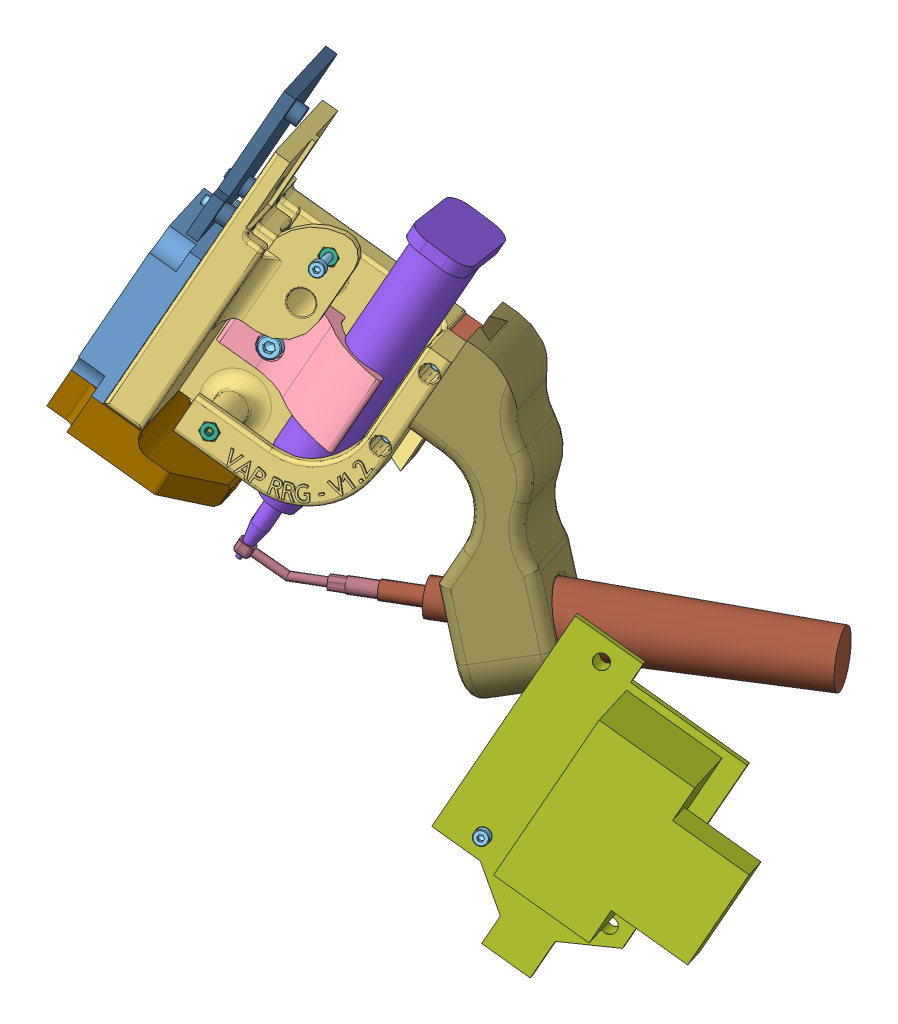
SolidWorks assembly nozzle4_assembly, configuration Default. Lengths in mm.
Overall size (190.12 193.79 108.62).
25 component instances, 13 part files, 57 mates.
Components (placement in the parent):
- fan-1: fan [Default] at (124.8712 147.7754 268.9855) x (0.468422 0.309997 0.827335) z (-0.270776 -0.840989 0.468422) size (40 10 40)
- nozzle4_QuickChange-1: nozzle4_QuickChange [Default] at (125.8081 148.3954 270.6402) x (0.840989 -0.443441 -0.309997) z (0.468422 0.309997 0.827335) size (8.5 30 13)
- nozzle4_quickmount-1: nozzle4_quickmount [Default] at (124.8712 147.7754 268.9855) x (0.840989 -0.443441 -0.309997) z (0.468422 0.309997 0.827335) size (60.2 70.01 40.1)
- syringe_clamp-1: syringe_clamp [Default] at (160.8249 151.5202 262.3349) x (0.840989 -0.443441 -0.309997) z (0.468422 0.309997 0.827335) size (35 20 18.86)
- socket head cap screw_am-1: socket head cap screw_am [B18.3.1M - 3 x 0.5 x 10 Hex SHCS -- 10NHX] at (157.0088 167.862 259.581) x (-0.468422 -0.309997 -0.827335) z (0.782372 0.289501 -0.551438) size (13 5.5 5.5)
- socket head cap screw_am-2: socket head cap screw_am [B18.3.1M - 3 x 0.5 x 10 Hex SHCS -- 10NHX] at (154.8426 161.1341 263.3283) x (-0.468422 -0.309997 -0.827335) z (0.782372 0.289501 -0.551438) size (13 5.5 5.5)
- hex nut style 1_am-1: hex nut style 1_am [B18.2.4.1M - Hex nut, Style 1,  M3 x 0.5 --D-N] at (150.1584 158.0341 255.055) x (0.801769 -0.542524 -0.250666) z (0.468422 0.309997 0.827335) size (5.5 6.35 2.4)
- hex nut style 1_am-2: hex nut style 1_am [B18.2.4.1M - Hex nut, Style 1,  M3 x 0.5 --D-N] at (152.3246 164.762 251.3076) x (0.879924 -0.079465 -0.468422) z (0.468422 0.309997 0.827335) size (5.5 6.35 2.4)
- hex nut style 1_am-3: hex nut style 1_am [B18.2.4.1M - Hex nut, Style 1,  M2 x 0.4 --D-N] at (180.5454 147.9149 248.0482) x (0.879924 -0.079465 -0.468422) z (0.468422 0.309997 0.827335) size (4 4.62 1.6)
- hex nut style 1_am-4: hex nut style 1_am [B18.2.4.1M - Hex nut, Style 1,  M2 x 0.4 --D-N] at (186.1565 164.225 238.5182) x (-0.59293 0.804525 0.034255) z (0.468422 0.309997 0.827335) size (4 4.62 1.6)
- socket head cap screw_am-3: socket head cap screw_am [B18.3.1M - 2 x 0.4 x 20 Hex SHCS -- 16NHX] at (192.1441 168.8266 249.6006) x (-0.468422 -0.309997 -0.827335) z (0.782372 0.289501 -0.551438) size (22 3.8 3.8)
- socket head cap screw_am-4: socket head cap screw_am [B18.3.1M - 2 x 0.4 x 20 Hex SHCS -- 16NHX] at (186.7286 152.0068 258.969) x (-0.468422 -0.309997 -0.827335) z (0.782372 0.289501 -0.551438) size (22 3.8 3.8)
- sensing_board-2: sensing_board [Default] at (239.1764 129.7752 254.7555) x (-0.270776 -0.840989 0.468422) z (-0.840989 0.443441 0.309997) size (73.67 39.39 63)
- hex nut style 1_am-5: hex nut style 1_am [B18.2.4.1M - Hex nut, Style 1,  M2 x 0.4 --D-N] at (158.2845 151.7288 284.8473) x (-0.840989 0.443441 0.309997) z (0.468422 0.309997 0.827335) size (4 4.62 1.6)
- hex nut style 1_am-7: hex nut style 1_am [B18.2.4.1M - Hex nut, Style 1,  M2 x 0.4 --D-N] at (171.5346 192.576 262.0401) x (-0.840989 0.443441 0.309997) z (0.468422 0.309997 0.827335) size (4 4.62 1.6)
- syringe_OG-2: syringe_OG [Default] at (166.2018 131.4069 272.2661) x (0.86938 -0.42258 -0.256132) z (0.41335 0.337882 0.845563) size (15.75 90.3 30.7)
- fan_flow-1: fan_flow [Default] at (113.7536 143.7999 276.7697) x (0.840989 -0.443441 -0.309997) z (0.468422 0.309997 0.827335) size (42.01 10.01 40)
- heater_board-1: heater_board [Default] at (161.4882 227.8853 263.4062) x (-0.468422 -0.309997 -0.827335) z (-0.840989 0.443441 0.309997) size (39 38 6)
- socket head cap screw_am-5: socket head cap screw_am [B18.3.1M - 2.5 x 0.45 x 10 Hex SHCS -- 10NHX] at (147.8158 190.0568 254.6203) x (-0.840989 0.443441 0.309997) z (0.180613 -0.309997 0.933424) size (12.5 4.5 4.5)
- socket head cap screw_am-6: socket head cap screw_am [B18.3.1M - 2.5 x 0.45 x 10 Hex SHCS -- 10NHX] at (157.1983 196.2661 271.1918) x (-0.840989 0.443441 0.309997) z (0.180613 -0.309997 0.933424) size (12.5 4.5 4.5)
- socket head cap screw_am-8: socket head cap screw_am [B18.3.1M - 2 x 0.4 x 10 Hex SHCS -- 10NHX] at (235.1514 81.6515 279.9009) x (-0.468422 -0.309997 -0.827335) z (0.079465 -0.947411 0.309997) size (12 3.8 3.8)
- socket head cap screw_am-9: socket head cap screw_am [B18.3.1M - 2 x 0.4 x 10 Hex SHCS -- 10NHX] at (176.3078 195.7349 270.4707) x (-0.468422 -0.309997 -0.827335) z (-0.079465 0.947411 -0.309997) size (12 3.8 3.8)
- dental_tool_model-1: dental_tool_model [Default] at (198.2647 115.692 258.946) x (-0.102236 -0.980703 -0.166639) z (-0.499941 0.195479 -0.84371) size (18 101.69 18)
- quick_change_dentalTool-1: quick_change_dentalTool [Default] at (187.717 137.5161 273.5079) x (0.840989 -0.443441 -0.309997) z (0.468422 0.309997 0.827335) size (58.56 68.56 37.55)
- tip_model-1: tip_model [Default] at (179.6026 115.7559 270.0191) x (0.860004 -0.002948 -0.510279) z (0.490154 0.282891 0.824452) size (32.23 9.09 4.04)
Mates (geometry in assembly coordinates):
- Coincident6: coincident: plane of nozzle4_QuickChange-1 through (153.3995 199.7448 272.0392) normal (0.270776 0.840989 -0.468422); plane of nozzle4_quickmount-1 through (152.4627 199.1248 270.3845) normal (0.270776 0.840989 -0.468422)
- Concentric3: concentric: cylinder of syringe_clamp-1 through (157.4773 168.172 260.4083) axis (0.468422 0.309997 0.827335) radius 3.25; cylinder of socket head cap screw_am-1 through (171.8812 177.7044 285.8488) axis (0.468422 0.309997 0.827335) radius 1.5
- Concentric4: concentric: cylinder of syringe_clamp-1 through (155.3111 161.4441 264.1557) axis (0.468422 0.309997 0.827335) radius 3.25; cylinder of socket head cap screw_am-2 through (169.715 170.9765 289.5962) axis (0.468422 0.309997 0.827335) radius 1.5
- Coincident8: coincident: plane of syringe_clamp-1 through (156.9492 166.2225 256.603) normal (0.468422 0.309997 0.827335); plane of socket head cap screw_am-1 through (154.4748 169.4224 256.8049) normal (-0.468422 -0.309997 -0.827335)
- Coincident9: coincident: plane of syringe_clamp-1 through (154.783 159.4946 260.3503) normal (0.468422 0.309997 0.827335); plane of socket head cap screw_am-2 through (152.3086 162.6945 260.5523) normal (-0.468422 -0.309997 -0.827335)
- Concentric5: concentric: cylinder of nozzle4_quickmount-1 through (156.9853 167.8464 259.5394) axis (-0.468422 -0.309997 -0.827335) radius 1.75; cylinder of socket head cap screw_am-1 through (171.8812 177.7044 285.8488) axis (0.468422 0.309997 0.827335) radius 1.5
- Coincident10: coincident: plane of nozzle4_quickmount-1 through (128.8528 150.4104 276.0179) normal (0.468422 0.309997 0.827335); plane of syringe_clamp-1 through (163.5258 167.5434 249.9671) normal (-0.468422 -0.309997 -0.827335)
- Concentric7: concentric: cylinder of socket head cap screw_am-2 through (169.715 170.9765 289.5962) axis (0.468422 0.309997 0.827335) radius 1.5; cylinder of hex nut style 1_am-1 through (149.0342 157.2901 253.0694) axis (0.468422 0.309997 0.827335) radius 1.25
- Coincident13: coincident: plane of nozzle4_quickmount-1 through (126.5107 148.8604 271.8812) normal (-0.468422 -0.309997 -0.827335); plane of hex nut style 1_am-1 through (145.7487 161.018 256.4336) normal (0.468422 0.309997 0.827335)
- Concentric8: concentric: cylinder of socket head cap screw_am-1 through (171.8812 177.7044 285.8488) axis (0.468422 0.309997 0.827335) radius 1.5; cylinder of hex nut style 1_am-2 through (151.2004 164.0181 249.322) axis (0.468422 0.309997 0.827335) radius 1.25
- Coincident15: coincident: plane of nozzle4_quickmount-1 through (126.5107 148.8604 271.8812) normal (-0.468422 -0.309997 -0.827335); plane of hex nut style 1_am-2 through (147.485 165.1991 253.8839) normal (0.468422 0.309997 0.827335)
- Concentric9: concentric: cylinder of nozzle4_quickmount-1 through (195.8914 171.3066 256.2193) axis (0.468422 0.309997 0.827335) radius 2.2; cylinder of socket head cap screw_am-3 through (207.0164 178.669 275.8685) axis (0.468422 0.309997 0.827335) radius 1
- Concentric10: concentric: cylinder of nozzle4_quickmount-1 through (190.4759 154.4868 265.5877) axis (0.468422 0.309997 0.827335) radius 2.2; cylinder of socket head cap screw_am-4 through (201.6009 161.8493 285.2369) axis (0.468422 0.309997 0.827335) radius 1
- Coincident16: coincident: plane of nozzle4_quickmount-1 through (192.3005 167.6301 247.5429) normal (0.468422 0.309997 0.827335); plane of socket head cap screw_am-3 through (190.4274 169.9272 247.7428) normal (-0.468422 -0.309997 -0.827335)
- Coincident17: coincident: plane of nozzle4_quickmount-1 through (186.885 150.8104 256.9113) normal (0.468422 0.309997 0.827335); plane of socket head cap screw_am-4 through (185.0118 153.1075 257.1112) normal (-0.468422 -0.309997 -0.827335)
- Coincident18: coincident: plane of nozzle4_QuickChange-1 through (190.6505 158.9966 235.9989) normal (0.270776 0.840989 -0.468422); plane of hex nut style 1_am-4 through (183.8944 162.559 238.4893) normal (-0.270776 -0.840989 0.468422)
- Coincident19: coincident: plane of nozzle4_QuickChange-1 through (191.7878 162.5288 234.0315) normal (0.468422 0.309997 0.827335); plane of hex nut style 1_am-4 through (187.7788 160.5109 237.0575) normal (-0.468422 -0.309997 -0.827335)
- Coincident20: coincident: plane of nozzle4_QuickChange-1 through (186.9561 132.8626 278.1004) normal (0.840989 -0.443441 -0.309997); line of hex nut style 1_am-4 through (187.4329 162.7603 236.6264) axis (0.468422 0.309997 0.827335)
- Concentric11: concentric: cylinder of hex nut style 1_am-3 through (179.7959 147.4189 246.7245) axis (0.468422 0.309997 0.827335) radius 0.8; cylinder of socket head cap screw_am-4 through (201.6009 161.8493 285.2369) axis (0.468422 0.309997 0.827335) radius 1
- Coincident23: coincident: plane of nozzle4_QuickChange-1 through (173.1359 130.681 266.1947) normal (0.468422 0.309997 0.827335); plane of nozzle4_quickmount-1 through (191.6349 120.9169 259.3794) normal (-0.468422 -0.309997 -0.827335)
- Coincident24: coincident: plane of nozzle4_QuickChange-1 through (175.752 130.4057 267.234) normal (-0.840989 0.443441 0.309997); plane of nozzle4_quickmount-1 through (174.8152 129.7857 265.5794) normal (0.840989 -0.443441 -0.309997)
- Coincident25: coincident: plane of nozzle4_quickmount-1 through (169.4214 189.8035 253.4991) normal (-0.654993 -0.506597 0.560664); plane of hex nut style 1_am-7 through (172.7798 192.1642 259.5555) normal (0.654993 0.506597 -0.560664)
- Coincident26: coincident: plane of nozzle4_quickmount-1 through (138.9239 157.0753 293.8056) normal (0.468422 0.309997 0.827335); plane of hex nut style 1_am-7 through (174.8986 190.8022 260.8001) normal (0.468422 0.309997 0.827335)
- Coincident27: coincident: plane of nozzle4_quickmount-1 through (167.9837 191.7544 253.5822) normal (0.185996 -0.950038 0.250666); plane of hex nut style 1_am-7 through (171.4105 194.0222 259.6346) normal (-0.185996 0.950038 -0.250666)
- Coincident31: coincident: plane of nozzle4_quickmount-1 through (152.1136 148.8808 278.632) normal (0.654993 0.506597 -0.560664); plane of hex nut style 1_am-5 through (155.5404 151.1486 284.6844) normal (-0.654993 -0.506597 0.560664)
- Coincident32: coincident: plane of nozzle4_quickmount-1 through (152.7702 150.9201 277.4961) normal (0.840989 -0.443441 -0.309997); plane of hex nut style 1_am-5 through (155.5404 151.1486 284.6844) normal (-0.840989 0.443441 0.309997)
- Coincident33: coincident: plane of nozzle4_quickmount-1 through (138.9239 157.0753 293.8056) normal (0.468422 0.309997 0.827335); point of hex nut style 1_am-5
- Parallel6: parallel: plane of nozzle4_quickmount-1 through (138.9239 157.0753 293.8056) normal (0.468422 0.309997 0.827335); plane of sensing_board-2 through (239.1764 129.7752 254.7555) normal (-0.468422 -0.309997 -0.827335)
- Parallel8: parallel: plane of nozzle4_quickmount-1 through (186.0192 132.2426 276.4457) normal (0.840989 -0.443441 -0.309997); plane of sensing_board-2 through (285.1324 112.503 265.4254) normal (0.840989 -0.443441 -0.309997)
- Parallel9: parallel: plane of nozzle4_quickmount-1 through (152.4627 199.1248 270.3845) normal (0.270776 0.840989 -0.468422); plane of syringe_clamp-1 through (177.766 158.9675 242.8019) normal (0.270776 0.840989 -0.468422)
- Concentric15: concentric: cylinder of nozzle4_quickmount-1 through (167.3149 134.8643 270.3403) axis (0.270776 0.840989 -0.468422) radius 8.5; cylinder of syringe_OG-2 through (185.5081 191.3694 238.8676) axis (-0.270776 -0.840989 0.468422) radius 7.6
- Distance2: distance = 2.5 mm: plane of sensing_board-2 through (238.4337 54.6776 265.9214) normal (-0.468422 -0.309997 -0.827335); cylinder of syringe_OG-2 through (161.937 118.1614 279.6437) axis (0.270776 0.840989 -0.468422) radius 2.3
- Coincident37: coincident: plane of fan-1 through (135.1982 164.6097 305.1789) normal (0.468422 0.309997 0.827335); plane of nozzle4_quickmount-1 through (143.6081 160.1753 302.0789) normal (0.468422 0.309997 0.827335)
- Coincident39: coincident: plane of nozzle4_QuickChange-1 through (187.2154 146.267 244.8892) normal (-0.468422 -0.309997 -0.827335); plane of hex nut style 1_am-3 through (177.0257 148.2327 249.9219) normal (0.468422 0.309997 0.827335)
- Parallel10: parallel: plane of fan-1 through (116.4614 152.2098 272.0855) normal (-0.270776 -0.840989 0.468422); plane of fan_flow-1 through (135.1982 164.6097 305.1789) normal (0.270776 0.840989 -0.468422)
- Coincident42: coincident: plane of nozzle4_quickmount-1 through (143.6081 160.1753 302.0789) normal (0.468422 0.309997 0.827335); plane of fan_flow-1 through (132.4905 156.1998 309.8631) normal (0.468422 0.309997 0.827335)
- Concentric18: concentric: cylinder of nozzle4_quickmount-1 through (149.4436 160.3462 295.0848) axis (-0.270776 -0.840989 0.468422) radius 1; cylinder of fan_flow-1 through (145.382 147.7313 302.1112) axis (-0.270776 -0.840989 0.468422) radius 2.2
- Coincident43: coincident: plane of nozzle4_quickmount-1 through (138.9239 157.0753 293.8056) normal (-0.270776 -0.840989 0.468422); plane of fan_flow-1 through (135.1982 164.6097 305.1789) normal (0.270776 0.840989 -0.468422)
- Parallel11: parallel: plane of fan-1 through (127.2924 185.8494 253.3487) normal (0.270776 0.840989 -0.468422); plane of heater_board-1 through (148.6757 197.2581 282.1362) normal (-0.270776 -0.840989 0.468422)
- Parallel12: parallel: plane of nozzle4_quickmount-1 through (138.9239 157.0753 293.8056) normal (-0.840989 0.443441 0.309997); plane of heater_board-1 through (158.9652 229.2156 264.3362) normal (-0.840989 0.443441 0.309997)
- Concentric19: concentric: cylinder of nozzle4_quickmount-1 through (161.4032 194.0489 269.6418) axis (0.840989 -0.443441 -0.309997) radius 1.35; cylinder of heater_board-1 through (150.4704 199.8136 273.6718) axis (-0.840989 0.443441 0.309997) radius 2
- Coincident48: coincident: plane of nozzle4_quickmount-1 through (138.9239 157.0753 293.8056) normal (-0.840989 0.443441 0.309997); plane of heater_board-1 through (152.9934 198.4833 272.7418) normal (0.840989 -0.443441 -0.309997)
- Concentric20: concentric: cylinder of heater_board-1 through (150.4704 199.8136 273.6718) axis (-0.840989 0.443441 0.309997) radius 2; cylinder of socket head cap screw_am-6 through (183.8997 182.1868 261.3494) axis (0.840989 -0.443441 -0.309997) radius 1.25
- Coincident49: coincident: plane of nozzle4_quickmount-1 through (155.4614 198.51 271.3345) normal (0.840989 -0.443441 -0.309997); plane of socket head cap screw_am-6 through (153.9483 195.4825 271.5604) normal (-0.840989 0.443441 0.309997)
- Concentric21: concentric: cylinder of heater_board-1 through (141.0879 193.6044 257.1003) axis (-0.840989 0.443441 0.309997) radius 2; cylinder of socket head cap screw_am-5 through (174.5172 175.9776 244.7779) axis (0.840989 -0.443441 -0.309997) radius 1.25
- Coincident50: coincident: plane of nozzle4_quickmount-1 through (146.0789 192.3008 254.7629) normal (0.840989 -0.443441 -0.309997); plane of socket head cap screw_am-5 through (144.5658 189.2732 254.9889) normal (-0.840989 0.443441 0.309997)
- Coincident52: coincident: plane of sensing_board-2 through (240.1133 130.3952 256.4102) normal (0.468422 0.309997 0.827335); circle of socket head cap screw_am-9
- Concentric24: concentric: cylinder of sensing_board-2 through (234.2146 81.0315 278.2462) axis (-0.468422 -0.309997 -0.827335) radius 2; cylinder of socket head cap screw_am-8 through (250.0238 91.4939 306.1688) axis (0.468422 0.309997 0.827335) radius 1
- Coincident53: coincident: plane of sensing_board-2 through (240.1133 130.3952 256.4102) normal (0.468422 0.309997 0.827335); circle of socket head cap screw_am-8
- Coincident54: coincident: plane of fan-1 through (124.8712 147.7754 268.9855) normal (0.840989 -0.443441 -0.309997); plane of nozzle4_quickmount-1 through (138.9239 157.0753 293.8056) normal (-0.840989 0.443441 0.309997)
- Concentric27: concentric: cylinder of fan-1 through (144.5509 195.9473 285.7242) axis (0.840989 -0.443441 -0.309997) radius 1.1; cylinder of nozzle4_quickmount-1 through (161.3706 187.0785 279.5243) axis (-0.840989 0.443441 0.309997) radius 1
- Coincident55: coincident: plane of nozzle4_quickmount-1 through (186.0192 132.2426 276.4457) normal (0.840989 -0.443441 -0.309997); plane of quick_change_dentalTool-1 through (192.3726 173.6868 234.3973) normal (-0.840989 0.443441 0.309997)
- Parallel15: parallel: line of nozzle4_quickmount-1 through (194.3888 170.8711 243.8946) axis (0.925893 -0.094359 0.365813); line of quick_change_dentalTool-1 through (200.7162 175.673 242.7863) axis (-0.925893 0.094359 -0.365813)
- Concentric28: concentric: cylinder of dental_tool_model-1 through (189.2347 115.7229 264.3039) axis (0.860004 -0.002948 -0.510279) radius 2.35; cylinder of tip_model-1 through (189.2347 115.7229 264.3039) axis (-0.860004 0.002948 0.510279) radius 2
- Coincident58: coincident: plane of dental_tool_model-1 through (189.2347 115.7229 264.3039) normal (-0.860004 0.002948 0.510279); plane of tip_model-1 through (189.2347 115.7229 264.3039) normal (0.860004 -0.002948 -0.510279)
- Coincident59: coincident: plane of nozzle4_quickmount-1 through (190.8949 145.1696 259.7763) normal (-0.263445 0.532761 0.804215); plane of quick_change_dentalTool-1 through (200.7162 175.673 242.7863) normal (0.263445 -0.532761 -0.804215)
- Concentric29: concentric: cone of syringe_OG-2 through (161.937 118.1614 279.6437) axis (-0.270776 -0.840989 0.468422); cylinder of tip_model-1 through (163.0592 121.6465 277.7025) axis (0.270776 0.840989 -0.468422) radius 1.45
